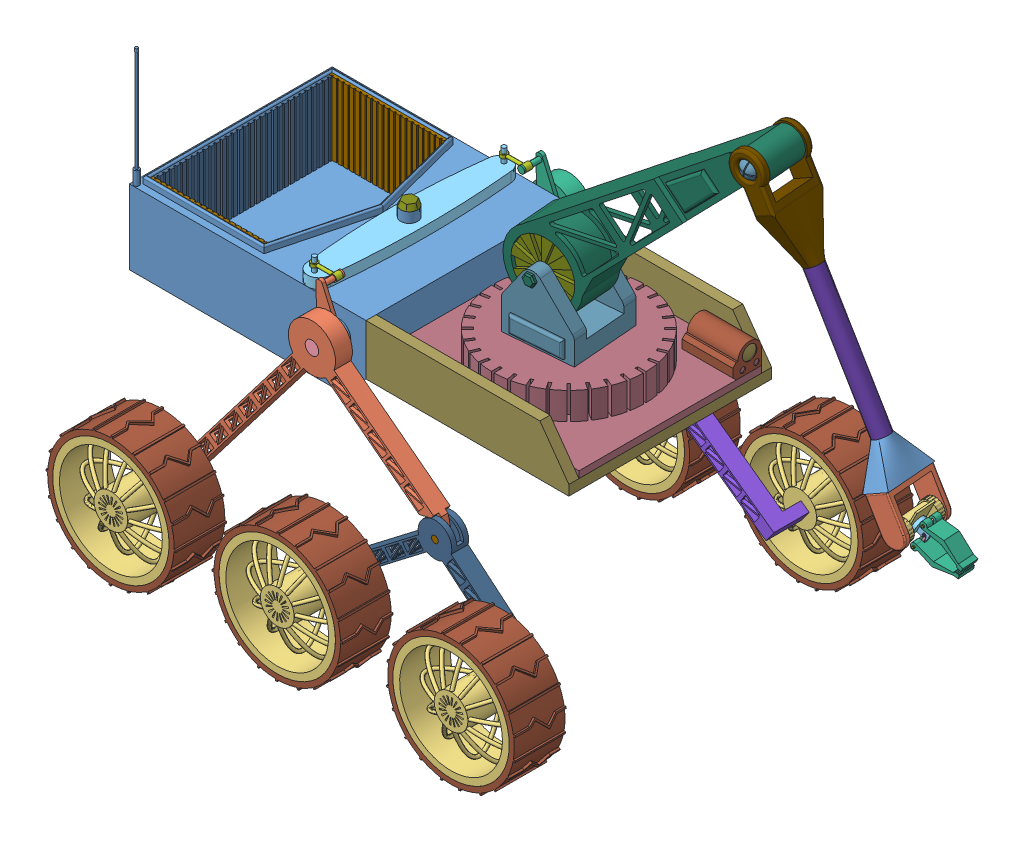
SolidWorks assembly FINAL_ROVERMODEL, configuration Default. Lengths in mm.
Overall size (2116.14 1680.02 1178.3).
61 component instances, 34 part files, 9 mates.
Components (placement in the parent):
- MARSROVERongoing-1: MARSROVERongoing [Default] at (-263.8828 135.0929 189.3247) size (2116.14 1680.02 1178.3)
  - MARSROVER-1: MARSROVER [Default] at (48.5084 415.5914 -65.9226) size (2005.6 1680.02 1178.3)
    - BASEMODELROVER-1: BASEMODELROVER [Default] at (-113.0741 81.444 751.2423) size (1666.1 1754.22 1178.3)
      - BASE-1: BASE [Default] at (425.3524 498.7093 360.0996) size (700 570 640)
      - ROVERSIDEROCKER-1: ROVERSIDEROCKER [Default] at (268.1879 557.6096 948.0327) x (0.999743 0.004759 -0.022165) z (0.022195 -0.006249 0.999734) size (980.94 901.23 326.24)
        - UPPERROCKER-1: UPPERROCKER [Default] at (499.6988 -437.5258 55.9375) x (0.975432 0.219369 0.020232) z (-0.022165 0.006353 0.999734) size (828.95 580.17 215)
        - ROVERRIM-1: ROVERRIM [Default] at (26.7864 -532.9503 146.0855) x (0.089152 0.996009 -0.004353) z (-0.022165 0.006353 0.999734) size (344.1 344.1 150)
      - basepin-1: basepin [Default] at (695.3524 538.7093 280.0996) x (-0.286198 -0.95817 0) z (0 0 1) size (40 40 760)
      - DIFFSUS-2: DIFFSUS [Default] at (603.1046 608.7093 660.0996) x (0.999998 0 0.001785) z (-0.001785 0 0.999998) size (97.31 70 600)
      - mirrorassem-1: mirrorassem [Default] at (433.2949 -54.1682 -296.8099) x (0.999364 -0.035655 0) z (0 0 1) size (958.31 910.95 315)
        - UPPERROCKERmirror-1: UPPERROCKERmirror [Default] at (327.7742 187.4834 756.9095) x (0.968136 0.250423 0) z (0 0 1) size (828.95 580.17 215)
        - ROVERRIM-1: ROVERRIM [Default] at (-139.7155 76.4336 526.9095) x (-0.02313 -0.999732 0) z (0 0 -1) size (344.1 344.1 150)
      - LINKAGE-3: LINKAGE [Default] at (668.9632 658.6965 370.1) size (85.36 20 20)
      - LINKAGE-4: LINKAGE [Default] at (667.9639 658.4724 930.0991) size (85.36 20 20)
      - FRONTROCKERmirror-1: FRONTROCKERmirror [Default] at (972.7502 22.1941 330.0996) x (0.998723 0.050521 0) z (0 0 1) size (570.26 284.33 150)
      - Lowerrockerpin-1: Lowerrockerpin [Default] at (1056.6379 226.6933 280.0996) x (0.999551 -0.02998 0) z (0 0 1) size (20 20 50)
      - FRONTROCKER-1: FRONTROCKER [Default] at (960.7442 31.8313 990.0996) x (0.999759 -0.021965 0) z (0 0 1) size (570.26 284.33 150)
      - Lowerrockerpin-2: Lowerrockerpin [Default] at (1059.2264 229.7159 990.0996) size (20 20 50)
      - ROVERRIM-1: ROVERRIM [Default] at (797.7467 29.1984 1095.0726) x (0.008676 -0.999962 0) z (0 0 1) size (344.1 344.1 150)
      - ROVERRIM-2: ROVERRIM [Default] at (1311.6474 17.9081 1094.8569) x (0.457512 0.889204 0) z (0 0 1) size (344.1 344.1 150)
      - ROVERRIM-3: ROVERRIM [Default] at (810.3717 7.7598 225.1266) x (-0.485115 0.87445 0) z (0 0 -1) size (344.1 344.1 150)
      - ROVERRIM-4: ROVERRIM [Default] at (1323.74 33.7286 225.3423) x (0.056378 0.998409 0) z (0 0 -1) size (344.1 344.1 150)
      - ROVERTYRE-1: ROVERTYRE [Default] at (810.3717 7.7598 225.1266) x (-0.485115 0.87445 0) z (0 0 -1) size (384.11 386 150.02)
      - ROVERTYRE-2: ROVERTYRE [Default] at (1323.74 33.7286 225.3423) x (0.056378 0.998409 0) z (0 0 -1) size (384.11 386 150.02)
      - ROVERTYRE-3: ROVERTYRE [Default] at (1311.6474 17.9081 1094.8569) x (0.457512 0.889204 0) z (0 0 1) size (384.11 386 150.02)
      - ROVERTYRE-4: ROVERTYRE [Default] at (797.7467 29.1984 1095.0726) x (0.008676 -0.999962 0) z (0 0 1) size (384.11 386 150.02)
      - ROVERTYRE-5: ROVERTYRE [Default] at (300.6715 23.8903 1090.0996) x (0.999754 -0.022199 0) z (0 0 1) size (384.11 386 150.02)
      - ROVERTYRE-6: ROVERTYRE [Default] at (296.3935 27.1983 80.0996) x (0.999757 0.022048 0) z (0 0 1) size (384.11 386 150.02)
      - acc-1: acc [Default] at (775.3524 458.7093 960.0996) size (600 150 600)
      - armbase-1: armbase [Default] at (1075.3524 488.7093 660.0996) x (0 0 -1) z (1 0 0) size (540 150 600)
      - Armbase2-1: Armbase2 [Default] at (1075.3524 588.7093 660.0996) x (0.996727 0 -0.080846) z (0.080846 0 0.996727) size (200 194.21 220)
      - Assem11-1: Assem11 [Default] at (208.9434 781.4129 -71.9167) x (0.949861 -0.303033 -0.077045) z (0.080846 0 0.996727) size (614.53 933.13 130)
        - MECHANICALARM-1: MECHANICALARM [Default] at (754.1523 216.8085 739.6659) x (0.894223 -0.447622 0) z (0 0 1) size (220 933.38 130)
        - armaccSLDPRT-1: armaccSLDPRT [Default] at (754.1523 216.8085 739.6659) x (-0.260598 -0.965447 0) z (0 0 1) size (175 175 120)
    - ran-1: ran [Default] at (1632.3865 1144.2062 1356.9883) x (0.465675 -0.88415 -0.037772) z (0.415984 0.181024 0.891172) size (400 50 50)
    - arm-1: arm [Default] at (1518.9207 1368.847 1426.3887) x (0.465675 -0.88415 -0.037772) z (0.080846 0 0.996727) size (304.08 100 160)
    - arm5SLDPRT-1: arm5SLDPRT [Default] at (1818.6563 790.5464 1341.8796) x (0.465675 -0.88415 -0.037772) z (0.077611 -0.001715 0.996982) size (110.01 80.02 150.02)
    - armlink-1: armlink [Default] at (1865.2238 702.1314 1338.1025) x (0.465675 -0.88415 -0.037772) z (-0.077611 0.001715 -0.996982) size (135 70 150)
    - ran2-1: ran2 [Default] at (1914.8957 613.6479 1374.2046) x (0.895017 -0.440437 -0.070431) z (0.077611 -0.001715 0.996982) size (60 85.05 130)
  - claw-1: claw [Default] at (1960.8971 1001.6102 1234.0235) x (0.435789 0.897138 -0.072325) z (0.895017 -0.440437 -0.070431) size (98.94 58 154.48)
    - link6SLDPRT-1: link6SLDPRT [Default] at (13.3311 30.0877 18.5948) x (0.427815 0 0.903866) z (-0.903866 0 0.427815) size (17.49 10 31.26)
    - link3-1: link3 [Default] at (22.1017 35.0897 -10.1552) size (40 40 40)
    - link6SLDPRT-2: link6SLDPRT [Default] at (30.8724 40.0877 18.5948) x (-0.19117 0 0.981557) z (0.981557 0 0.19117) size (17.49 10 31.26)
    - clampSLDPRT-1: clampSLDPRT [Default] at (-11.6509 10.0877 20.0007) x (0.979433 0 -0.201768) z (0.201768 0 0.979433) size (29.36 50 133.85)
    - clampSLDPRT-2: clampSLDPRT [Default] at (55.4269 60.0877 13.7832) x (-0.999767 0 -0.021603) z (-0.021603 0 0.999767) size (29.36 50 133.85)
    - pinPart11-1: pinPart11 [Default] at (55.4269 10.0877 13.7832) x (0.156709 0 -0.987645) z (0.987645 0 0.156709) size (7.44 58 6.44)
    - pinPart11-2: pinPart11 [Default] at (-11.6509 10.0877 20.0007) size (7.44 58 6.44)
    - pinPart12-1: pinPart12 [Default] at (13.3311 30.0877 18.5948) x (-0.969493 0 -0.245118) z (0.245118 0 -0.969493) size (6.84 14 5.93)
    - pinPart12-2: pinPart12 [Default] at (30.8724 30.0877 18.5948) size (6.84 14 5.93)
  - insulator-2: insulator [Default] at (210.8367 1013.2447 1075.4193) x (0 0 1) z (-1 0 0) size (10 215 340.1)
  - insulator2-2: insulator2 [Default] at (40.7867 1013.2447 1345.4193) size (10 215 520)
  - insulator-3: insulator [Default] at (210.8367 1013.2447 1615.4193) x (0 0 -1) z (1 0 0) size (10 215 340.1)
  - rovercamera-1: rovercamera [Default] at (1219.7518 983.7089 1050.8045)
- camera1-1: camera1 [Default] at (902.3059 1081.6589 1178.8105) size (152.5 80 85)
  - cam-1: cam [Default] at (69.598 59.1788 120.9335) size (150 80 85)
  - Part2-1: Part2 [Default] at (139.598 109.3315 120.9335) x (1 0 0) z (0 -0.974794 -0.223109) size (7.5 42.74 42.74)
  - Part3-1: Part3 [Default] at (139.598 74.7804 141.1326) size (4.5 16.37 16.37)
  - Part3-2: Part3 [Default] at (139.598 74.7804 100.7344) size (4.5 16.37 16.37)
- pin13-1: pin13 [Default] at (1292.8746 1919.5313 1418.2229) x (-0.209661 -0.977626 0.017006) z (0.080846 0 0.996727) size (50 50 173.84)
- Part4-1: Part4 [Default] at (718.8848 1391.6225 1436.6883) x (0.996727 0 -0.080846) z (0.080846 0 0.996727) size (36.68 31.76 220)
- cap-1: cap [Default] at (274.656 1300.8377 1534.744) size (50.02 15.02 50.02)
Mates (geometry in assembly coordinates):
- Coincident1: coincident anti-aligned: plane of MARSROVERongoing-1/MARSROVER-1/BASEMODELROVER-1/armbase-1 through (746.9039 1140.8377 1534.744) normal (0 1 0); plane of camera1-1/cam-1 through (971.9039 1140.8377 1299.744) normal (0 -1 0)
- Coincident2: coincident anti-aligned: plane of MARSROVERongoing-1/MARSROVER-1/BASEMODELROVER-1/acc-1 through (1046.9039 1120.8377 1264.744) normal (0 0 1); plane of camera1-1/cam-1 through (896.9039 1220.8377 1264.744) normal (0 0 -1)
- Coincident3: coincident aligned: plane of MARSROVERongoing-1/MARSROVER-1/BASEMODELROVER-1/armbase-1 through (1046.9039 1140.8377 1804.744) normal (1 0 0); plane of camera1-1/cam-1 through (1046.9039 1220.8377 1334.744) normal (1 0 0)
- Concentric1: concentric anti-aligned: cylinder of MARSROVERongoing-1/MARSROVER-1/BASEMODELROVER-1/Assem11-1/MECHANICALARM-1 through (1293.8448 1919.5313 1430.1837) axis (0.080846 0 0.996727) radius 25; cylinder of pin13-1 through (1304.5165 1919.5313 1561.7516) axis (-0.080846 0 -0.996727) radius 25
- Coincident4: coincident aligned: circle of MARSROVERongoing-1/MARSROVER-1/arm-1; circle of pin13-1
- Concentric2: concentric anti-aligned: cylinder of MARSROVERongoing-1/MARSROVER-1/BASEMODELROVER-1/Armbase2-1 through (715.6509 1391.6225 1396.8192) axis (0.080846 0 0.996727) radius 15; cylinder of Part4-1 through (735.054 1391.6225 1636.0336) axis (-0.080846 0 -0.996727) radius 15
- Coincident5: coincident anti-aligned: plane of MARSROVERongoing-1/MARSROVER-1/BASEMODELROVER-1/Armbase2-1 through (655.3159 1520.8377 1642.5013) normal (0.080846 0 0.996727); plane of Part4-1 through (735.054 1391.6225 1636.0336) normal (-0.080846 0 -0.996727)
- Coincident7: coincident: plane of MARSROVERongoing-1/MARSROVER-1/BASEMODELROVER-1/BASE-1 through (274.656 1300.8377 1534.744) normal (0 1 0); plane of cap-1 through (274.656 1300.8377 1534.744) normal (0 -1 0)
- Coincident8: coincident aligned: circle of MARSROVERongoing-1/MARSROVER-1/BASEMODELROVER-1/BASE-1; circle of cap-1
